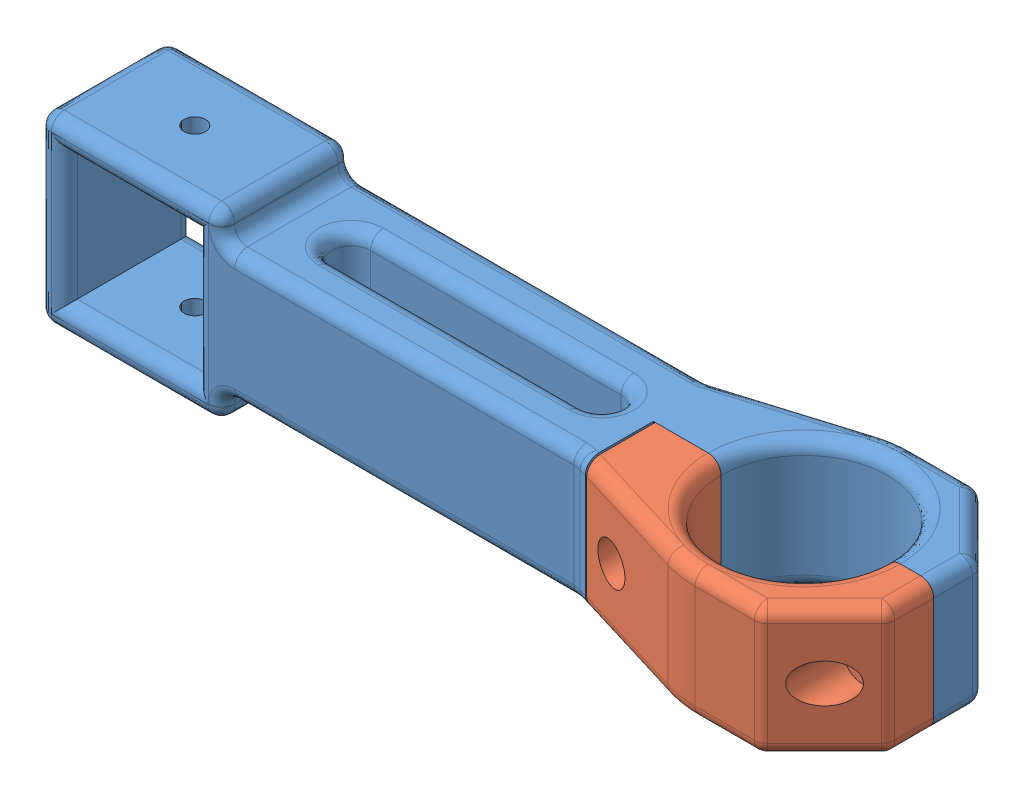
SolidWorks assembly 2020_mount_assembly, configuration 默认. Lengths in mm.
Overall size (128.3 28.3 33.7).
2 component instances, 2 part files, 3 mates.
Components (placement in the parent):
- 2020_mount_v2-1: 2020_mount_v2 [Default] at origin size (128.3 28.3 27.37)
- 2020_mount_2-1: 2020_mount_2 [Default] at (55 0 0) size (43 20 16.85)
Mates (geometry in assembly coordinates):
- Concentric1: concentric anti-aligned: cylinder of 2020_mount_v2-1 through (76.65 0 -16.85) axis (0 0 1) radius 1.65; cylinder of 2020_mount_2-1 through (76.65 0 26) axis (0 0 -1) radius 3
- Concentric2: concentric anti-aligned: cylinder of 2020_mount_v2-1 through (109.15 0 -16.85) axis (0 0 1) radius 1.65; cylinder of 2020_mount_2-1 through (109.15 0 26) axis (0 0 -1) radius 3
- Coincident1: coincident anti-aligned: plane of 2020_mount_v2-1 through (70.85 -14.15 0) normal (0 0 1); plane of 2020_mount_2-1 through (71.15 -14.15 0) normal (0 0 -1)
